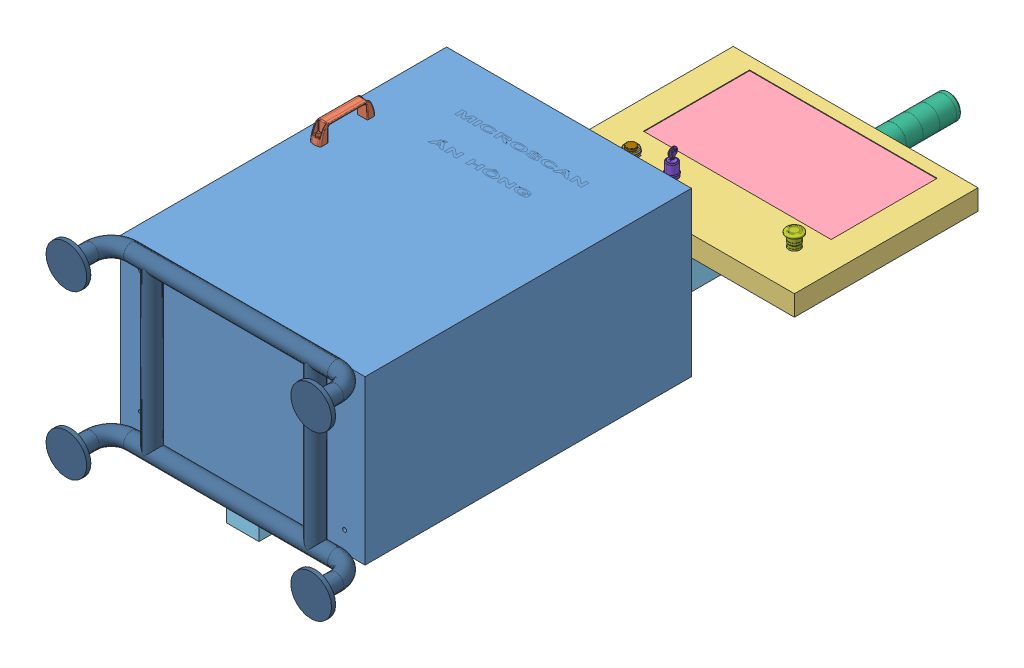
SolidWorks assembly tu dien, configuration Default. Lengths in mm.
Overall size (700 530 1862.4).
29 component instances, 28 part files, 25 mates.
Components (placement in the parent):
- tu dien-1: tu dien [Default] at (221.8904 379.7546 416.37) size (600 400 800)
- 8020-2061-$PARTNUMBER-1: 8020-2061-$PARTNUMBER [Default] at (-32.7798 579.7546 716.6699) x (0 0 1) z (-1 0 0) size (139.17 41.43 26.33)
- bat man hinh-1: bat man hinh [Default] at (221.8904 179.7546 -61.13) x (1 0 0) z (0 1 0) size (600 450 50)
- man hinh-1: man hinh [Default] at (221.8904 208.2546 -126.13) x (1 0 0) z (0 1 0) size (500 300 20)
- thanh bat man hinh-1: thanh bat man hinh [Default] at (221.8904 139.7546 -283.63) size (80 80 1500)
- User Library-p000557 light tower-1: User Library-p000557 light tower [Default] at (221.8904 139.7546 -283.63) x (0.032421 0.999474 0) z (-0.999474 0.032421 0) size (60 245.1 60)
- User Library-E Stop Button-1: User Library-E Stop Button [Default] at (421.8904 241.2546 63.87) size (39 70.54 39)
- G_IC03_XX_28762V-1: G_IC03_XX_28762V [Default] at (121.8933 229.7546 64.07) x (-0.999896 0 0.014408) z (0.014408 0 0.999896) size (29.48 86.4 29.48)
- dr30e3l-l3gzc-1: dr30e3l-l3gzc [Default] at (23.1032 185.1546 64.858) x (0.429366 0 0.903131) z (0 1 0) size (41 40.2 73.47)
  - dr30e3l-l3gzc_01-1: dr30e3l-l3gzc_01 [Default] at origin size (6.6 6.56 0.7)
  - dr30e3l-l3gzc_02-1: dr30e3l-l3gzc_02 [Default] at origin size (7.7 7.7 1.5)
  - dr30e3l-l3gzc_03-1: dr30e3l-l3gzc_03 [Default] at origin size (39 39 1.5)
  - dr30e3l-l3gzc_04-1: dr30e3l-l3gzc_04 [Default] at origin size (9.1 7.7 3)
  - dr30e3l-l3gzc_05-1: dr30e3l-l3gzc_05 [Default] at origin size (39 39 1.5)
  - dr30e3l-l3gzc_06-1: dr30e3l-l3gzc_06 [Default] at origin size (7.7 7.7 1.5)
  - dr30e3l-l3gzc_07-1: dr30e3l-l3gzc_07 [Default] at origin size (9.1 7.7 3)
  - dr30e3l-l3gzc_08-1: dr30e3l-l3gzc_08 [Default] at origin size (6.6 6.56 0.7)
  - dr30e3l-l3gzc_09-1: dr30e3l-l3gzc_09 [Default] at origin size (7.54 7.17 9.3)
  - dr30e3l-l3gzc_10-1: dr30e3l-l3gzc_10 [Default] at origin size (18.4 29 8.21)
  - dr30e3l-l3gzc_11-1: dr30e3l-l3gzc_11 [Default] at origin size (10 10.77 19.53)
  - dr30e3l-l3gzc_12-1: dr30e3l-l3gzc_12 [Default] at origin size (41 40.2 27.4)
  - dr30e3l-l3gzc_13-1: dr30e3l-l3gzc_13 [Default] at origin size (35 35 10)
  - dr30e3l-l3gzc_14-1: dr30e3l-l3gzc_14 [Default] at origin size (39 39 1.5)
  - dr30e3l-l3gzc_15-1: dr30e3l-l3gzc_15 [Default] at origin size (6.5 6.5 9.3)
  - dr30e3l-l3gzc_16-1: dr30e3l-l3gzc_16 [Default] at origin size (19.8 29.9 44.3)
  - dr30e3l-l3gzc_17-1: dr30e3l-l3gzc_17 [Default] at origin size (26.07 30 22.8)
  - dr30e3l-l3gzc_18-1: dr30e3l-l3gzc_18 [Default] at origin size (39 39 1.5)
  - dr30e3l-l3gzc_19-1: dr30e3l-l3gzc_19 [Default] at origin size (29.15 29.06 9.16)
- chan de tu-1: chan de tu [Default] at (-80.13 179.7546 1336.37) x (1 0 0) z (0 1 0) size (700 130 500)
Mates (geometry in assembly coordinates):
- Coincident7: coincident anti-aligned: plane of tu dien-1 through (521.8904 579.7546 1216.37) normal (0 1 0); plane of 8020-2061-$PARTNUMBER-1 through (-19.7788 579.7546 647.1687) normal (0 -1 0)
- Distance5: distance = 50 mm: line of 8020-2061-$PARTNUMBER-1 through (-45.1239 617.3304 763.084) axis (0 0 -1); line of tu dien-1 through (-78.1096 579.7546 1216.37) axis (0 0 -1)
- Distance6: distance = 250 mm: plane of 8020-2061-$PARTNUMBER-1 through (-40.7808 618.281 667.0806) normal (0 0.017452 -0.999848); line of tu dien-1 through (521.8904 579.7546 416.37) axis (-1 0 0)
- Coincident10: coincident anti-aligned: plane of bat man hinh-1 through (252.0913 228.2546 -61.13) normal (0 -1 0); plane of man hinh-1 through (252.0913 228.2546 -126.13) normal (0 1 0)
- Coincident13: coincident: plane of bat man hinh-1 through (22.0913 179.7536 -256.13) normal (0 0 1); line of man hinh-1 through (482.0913 228.2546 -256.13) axis (-1 0 0)
- Coincident14: coincident: plane of bat man hinh-1 through (22.0913 179.7536 -256.13) normal (1 0 0); line of man hinh-1 through (22.0913 228.2546 -256.13) axis (0 0 1)
- Parallel3: parallel aligned: plane of tu dien-1 through (521.8904 579.7546 1216.37) normal (0 1 0); plane of bat man hinh-1 through (252.0913 229.7546 -61.13) normal (0 1 0)
- Parallel4: parallel aligned: plane of tu dien-1 through (-78.1096 179.7546 1216.37) normal (-1 0 0); plane of bat man hinh-1 through (-47.9087 229.7546 -286.13) normal (-1 0 0)
- Distance7: distance = 1 mm anti-aligned: plane of thanh bat man hinh-1 through (221.8904 139.7546 -283.63) normal (0 0 -1); plane of bat man hinh-1 through (521.8904 229.7546 -284.63) normal (0 0 1)
- Distance8: distance = 260 mm aligned: plane of thanh bat man hinh-1 through (261.8904 99.7546 1216.37) normal (1 0 0); plane of bat man hinh-1 through (521.8904 229.7546 -286.13) normal (1 0 0)
- Concentric5: concentric aligned: cylinder of thanh bat man hinh-1 through (252.0913 139.7546 -283.63) axis (0 0 1) radius 7.696; cylinder of User Library-p000557 light tower-1 through (252.0913 139.7546 -516.03) axis (0 0 1) radius 30
- Coincident20: coincident anti-aligned: plane of thanh bat man hinh-1 through (252.0913 139.7546 -283.63) normal (0 0 -1); plane of User Library-p000557 light tower-1 through (252.0913 139.7546 -283.63) normal (0 0 1)
- Concentric6: concentric anti-aligned: cylinder of bat man hinh-1 through (452.0913 179.7536 63.87) axis (0 1 0) radius 11; cylinder of User Library-E Stop Button-1 through (452.0913 228.2546 63.87) axis (0 -1 0) radius 13
- Coincident21: coincident anti-aligned: plane of bat man hinh-1 through (252.0913 228.2546 -61.13) normal (0 -1 0); plane of User Library-E Stop Button-1 through (469.5913 228.2546 78.37) normal (0 1 0)
- Concentric7: concentric anti-aligned: cylinder of bat man hinh-1 through (152.0913 179.7536 63.87) axis (0 1 0) radius 11; cylinder of G_IC03_XX_28762V-1 through (152.0913 203.5546 63.87) axis (0 -1 0) radius 9.8
- Coincident22: coincident anti-aligned: plane of bat man hinh-1 through (252.0913 229.7546 -61.13) normal (0 1 0); plane of G_IC03_XX_28762V-1 through (152.2699 229.7546 76.2688) normal (0 -1 0)
- Concentric8: concentric aligned: cylinder of bat man hinh-1 through (52.0913 179.7536 63.87) axis (0 1 0) radius 11; cylinder of dr30e3l-l3gzc-1/dr30e3l-l3gzc_19-1 through (52.0913 240.0546 63.87) axis (0 1 0) radius 12
- Coincident23: coincident aligned: plane of bat man hinh-1 through (252.0913 229.7546 -61.13) normal (0 1 0); plane of dr30e3l-l3gzc-1/dr30e3l-l3gzc_18-1 through (52.0913 229.7546 63.87) normal (0 1 0)
- Coincident25: coincident: line of tu dien-1 through (521.8904 579.7546 1216.37) axis (-1 0 0); cylinder of chan de tu-1 through (-30.13 579.7546 1236.37) axis (1 0 0) radius 20
- Distance9: distance = 80 mm: cylinder of chan de tu-1 through (19.87 579.7546 1236.37) axis (0 -1 0) radius 20; line of tu dien-1 through (-78.1096 579.7546 1216.37) axis (0 -1 0)
- Distance10: distance = 120 mm anti-aligned: plane of chan de tu-1 through (-80.13 179.7546 1336.37) normal (0 0 -1); plane of tu dien-1 through (221.8904 379.7546 1216.37) normal (0 0 1)
- Coincident32: coincident aligned: plane of tu dien-1 through (221.8904 379.7546 1216.37) normal (0 0 1); plane of thanh bat man hinh-1 through (252.0913 139.7546 1216.37) normal (0 0 1)
- Coincident33: coincident anti-aligned: plane of bat man hinh-1 through (221.8904 179.7546 -61.13) normal (0 -1 0); plane of thanh bat man hinh-1 through (261.8904 179.7546 1216.37) normal (0 1 0)
- Coincident34: coincident anti-aligned: plane of tu dien-1 through (521.8904 179.7546 1216.37) normal (0 -1 0); plane of thanh bat man hinh-1 through (261.8904 179.7546 1216.37) normal (0 1 0)
- Coincident35: coincident aligned: plane of tu dien-1 through (521.8904 179.7546 1216.37) normal (1 0 0); plane of bat man hinh-1 through (521.8904 229.7546 -286.13) normal (1 0 0)
